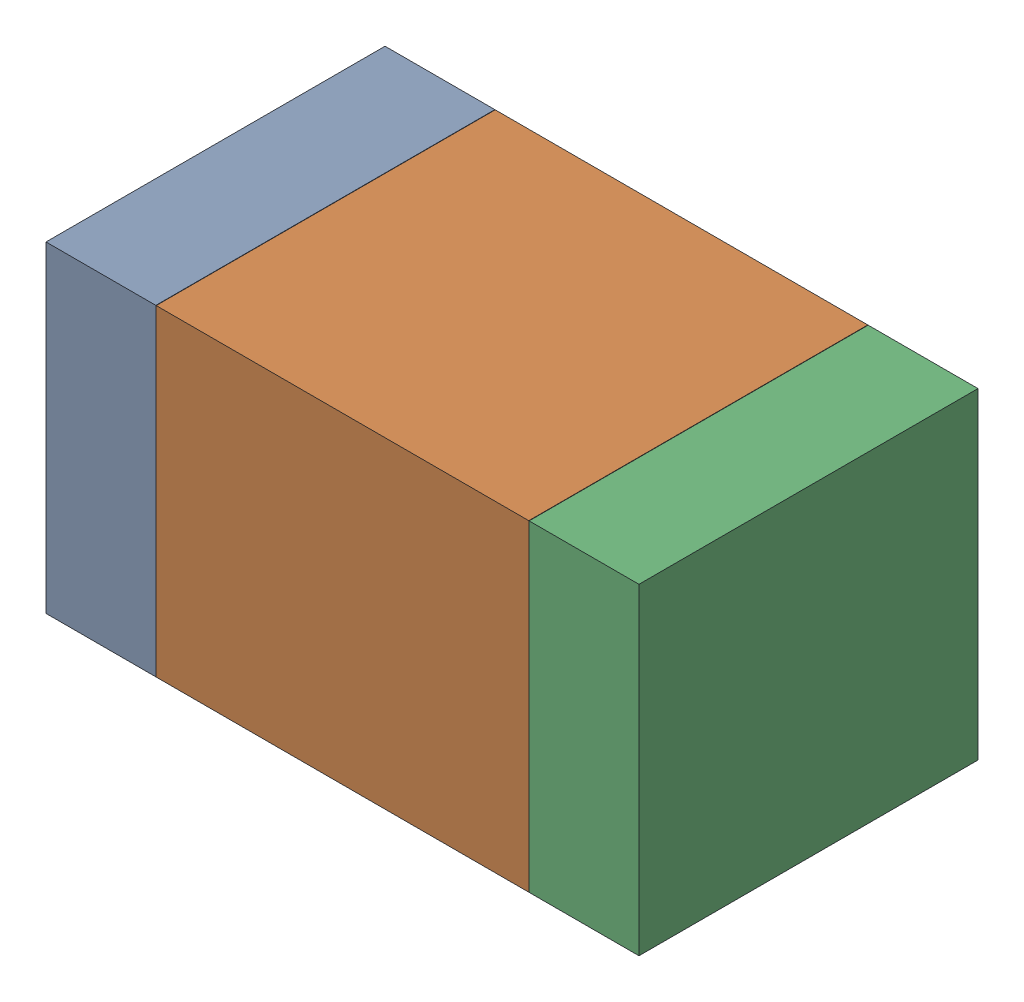
SolidWorks assembly C6, configuration Default. Lengths in mm.
Overall size (1.75 0.95 1).
6 component instances, 2 part files, 0 mates.
Components (placement in the parent):
- 6575498272-1: 6575498272 [Default] at (36.6255 21.59 0) size (0.32 0.95 1)
  - Extruded_8-1: Extruded_8 [Default] at origin size (0.32 0.95 1)
- 6575498112-1: 6575498112 [Default] at (37.338 21.59 0) size (1.1 0.95 1)
  - Extruded_9-1: Extruded_9 [Default] at origin size (1.1 0.95 1)
- 6575498272-2: 6575498272 [Default] at (38.0505 21.59 0) size (0.32 0.95 1)
  - Extruded_8-1: Extruded_8 [Default] at origin size (0.32 0.95 1)
